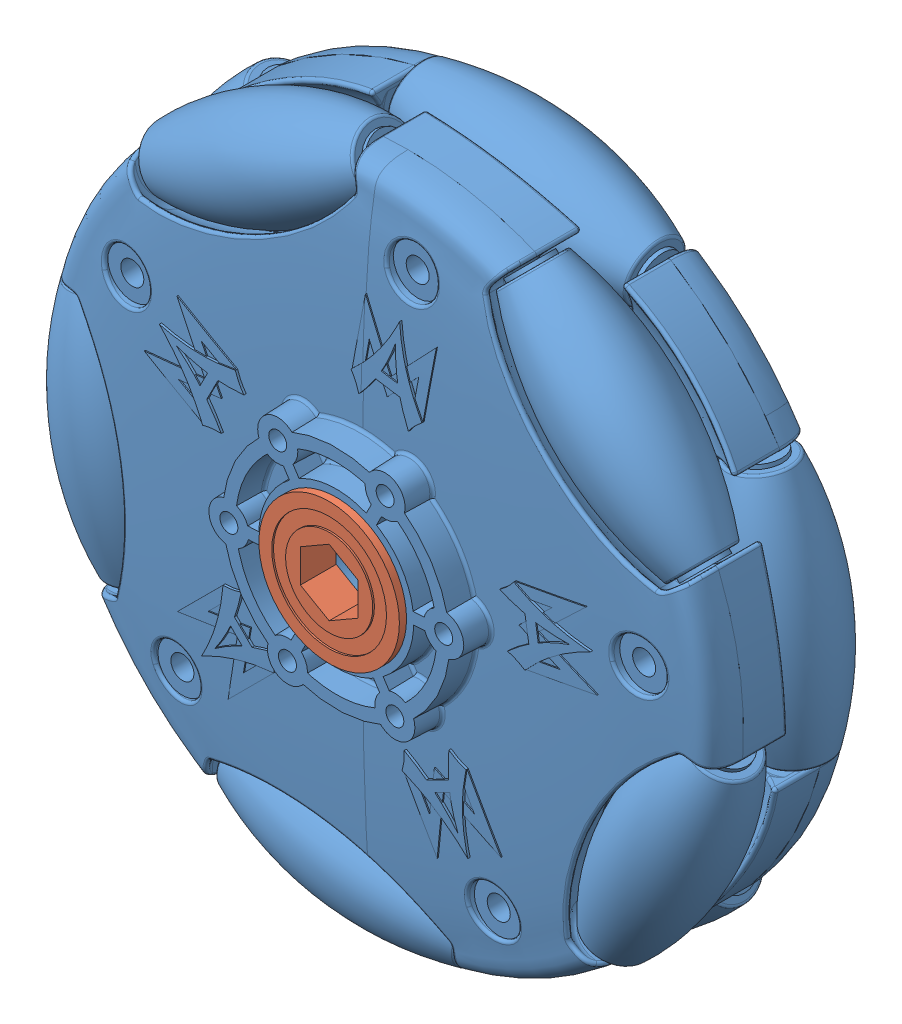
SolidWorks assembly omni plus bearings, configuration Default. Lengths in mm.
Overall size (179.34 179.34 93.3).
3 component instances, 2 part files, 4 mates.
Components (placement in the parent):
- omni wheel part-1: omni wheel part [Default] at (27.0172 100.7923 167.4611) size (179.34 179.34 93.3)
- hexbearing0.5-1: hexbearing0.5 [Default] at (27.0172 100.7923 177.6211) x (0 1 0) z (1 0 0) size (31.12 7.94 31.12)
- hexbearing0.5-2: hexbearing0.5 [Default] at (27.0172 100.7923 139.5211) x (1 0 0) z (0 1 0) size (31.12 7.94 31.12)
Mates (geometry in assembly coordinates):
- Concentric2: concentric aligned: cylinder of omni wheel part-1 through (27.0172 100.7923 142.1881) axis (0 0 -1) radius 14.2812; cylinder of hexbearing0.5-2 through (27.0172 100.7923 139.5211) axis (0 0 -1) radius 14.2748
- Coincident1: coincident aligned: plane of omni wheel part-1 through (27.0172 100.7923 133.1711) normal (0 0 -1); circle of hexbearing0.5-2
- Concentric5: concentric aligned: cylinder of omni wheel part-1 through (27.0172 100.7923 174.9541) axis (0 0 1) radius 14.2812; cylinder of hexbearing0.5-1 through (27.0172 100.7923 177.6211) axis (0 0 1) radius 14.2748
- Coincident2: coincident aligned: plane of omni wheel part-1 through (27.0172 100.7923 183.9711) normal (0 0 1); circle of hexbearing0.5-1
